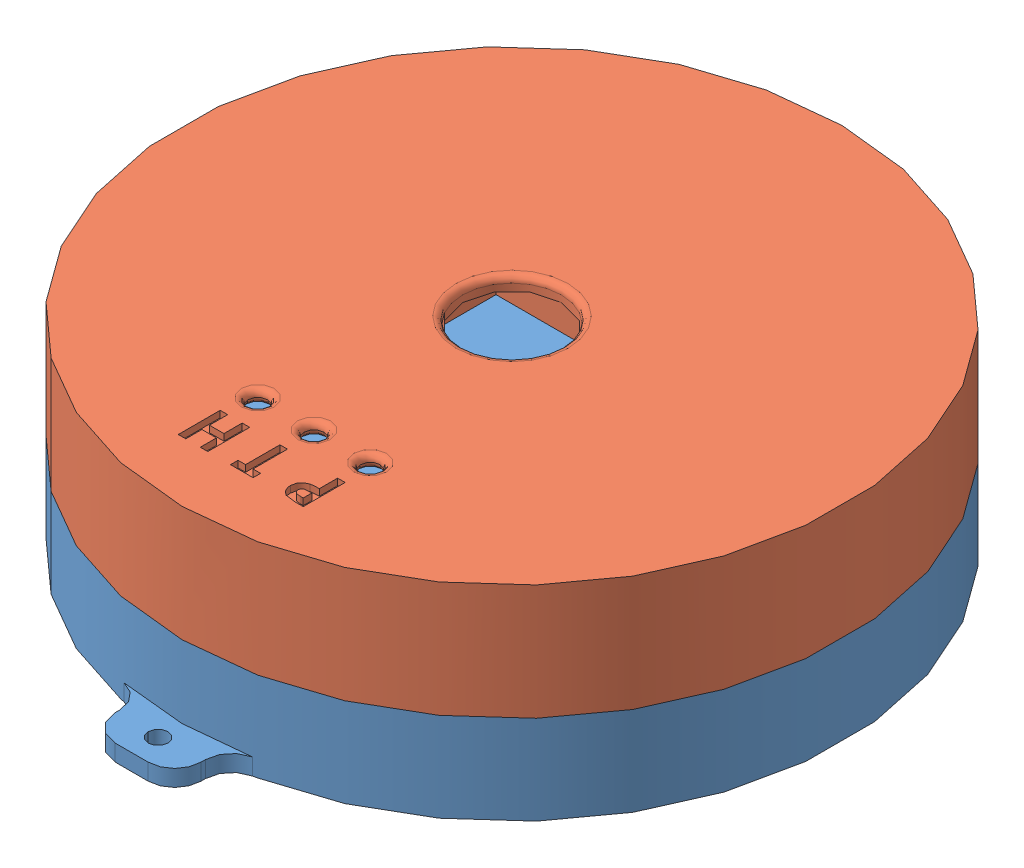
SolidWorks assembly CC Boc Assembly, configuration Default. Lengths in mm.
Overall size (100 31 107.63).
2 component instances, 2 part files, 3 mates.
Components (placement in the parent):
- CC Box Bottom-1: CC Box Bottom [Default] at origin size (100 15 107.63)
- CC Box Top-1: CC Box Top [Default] at (0 31 0) x (-1 0 0) z (0 0 1) size (100 17.5 100)
Mates (geometry in assembly coordinates):
- Coincident1: coincident: plane of CC Box Bottom-1 through (0 13.5 0) normal (0 1 0); plane of CC Box Top-1 through (0 13.5 0) normal (0 -1 0)
- Concentric1: concentric: cylinder of CC Box Bottom-1 through (0 15 0) axis (0 -1 0) radius 50; cylinder of CC Box Top-1 through (0 13.5 0) axis (0 1 0) radius 50
- Concentric2: concentric anti-aligned: circle of CC Box Bottom-1; circle of CC Box Top-1
